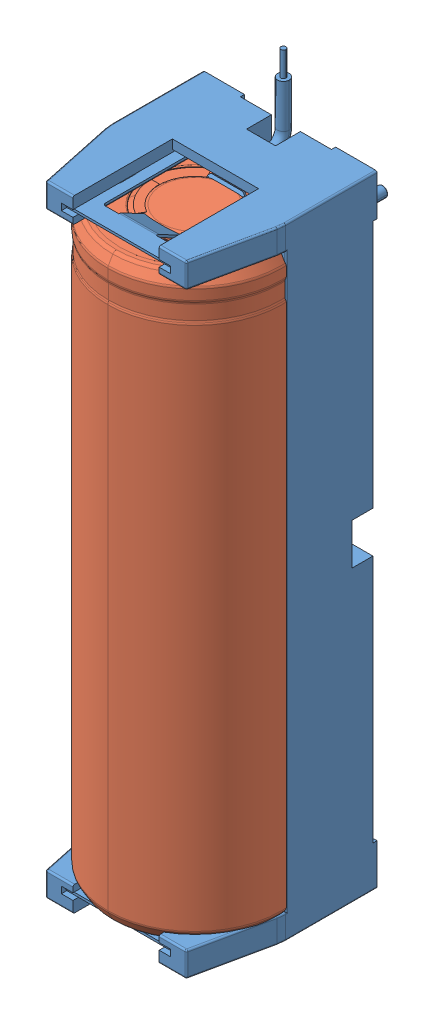
SolidWorks assembly Power, configuration Default. Lengths in mm.
Overall size (21.01 91 23.5).
2 component instances, 2 part files, 2 mates.
Components (placement in the parent):
- Battery Holder.stp-1: Battery Holder.stp [Default] at (-10.3221 -7.8579 1.0354) size (21.01 91 22.5)
- Battery-1: Battery [Default] at (-10.3221 -43.3579 12.5354) size (21 70.03 21)
Mates (geometry in assembly coordinates):
- Concentric1: concentric: cylinder of Battery Holder.stp-1 through (-10.3221 -7.8579 12.5354) axis (0 1 0) radius 9.5; cylinder of Battery-1 through (-10.3221 26.6421 12.5354) axis (0 -1 0) radius 10.5
- Coincident1: coincident anti-aligned: plane of Battery Holder.stp-1 through (-10.3221 26.6421 1.0354) normal (0 -1 0); plane of Battery-1 through (-10.3221 26.6421 3.5354) normal (0 1 0)
